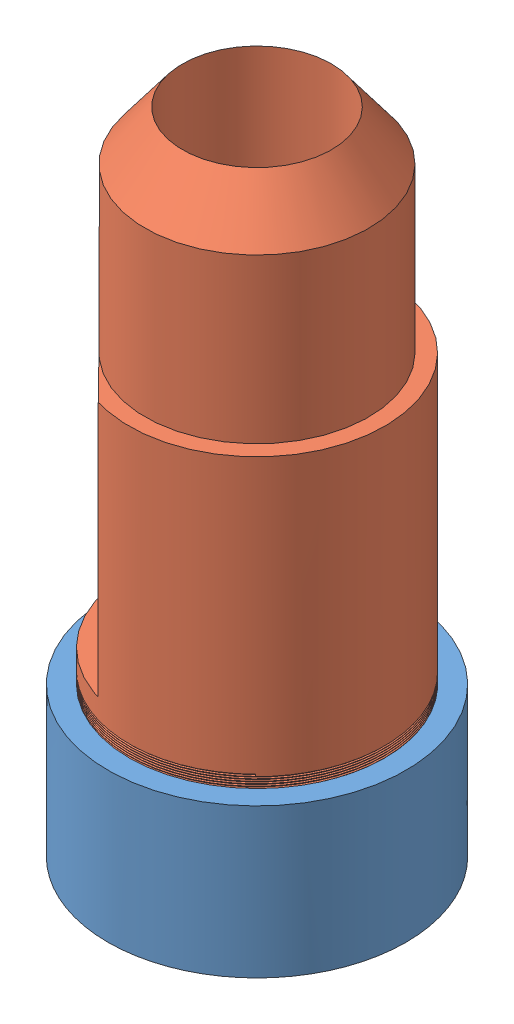
SolidWorks assembly NozzleAssembly, configuration Default. Lengths in mm.
Overall size (75.89 100 76.12).
2 component instances, 2 part files, 2 mates.
Components (placement in the parent):
- 09-04 Dreidel Nozzle_robot_03-1: 09-04 Dreidel Nozzle_robot_03 [Default] at (10.8892 0.1815 -14.5047) size (44.45 25.42 44.45)
- 09-04 Dreidel Nozzle_robot_01-1: 09-04 Dreidel Nozzle_robot_01 [Default] at (10.8892 4.9312 -14.5047) x (0.701277 0 0.712889) z (-0.712889 0 0.701277) size (63.5 95.25 43.99)
Mates (geometry in assembly coordinates):
- Concentric1: concentric: cylinder of 09-04 Dreidel Nozzle_robot_03-1 through (10.8892 3.3565 -14.5047) axis (0 1 0) radius 22.225; cylinder of 09-04 Dreidel Nozzle_robot_01-1 through (10.8892 128.0359 -14.5047) axis (0 -1 0) radius 19.05
- Coincident1: coincident aligned: cone of 09-04 Dreidel Nozzle_robot_03-1 through (10.8892 8.1062 -14.5047) axis (0 -1 0); cone of 09-04 Dreidel Nozzle_robot_01-1 through (10.8892 4.9312 -14.5047) axis (0 -1 0)
